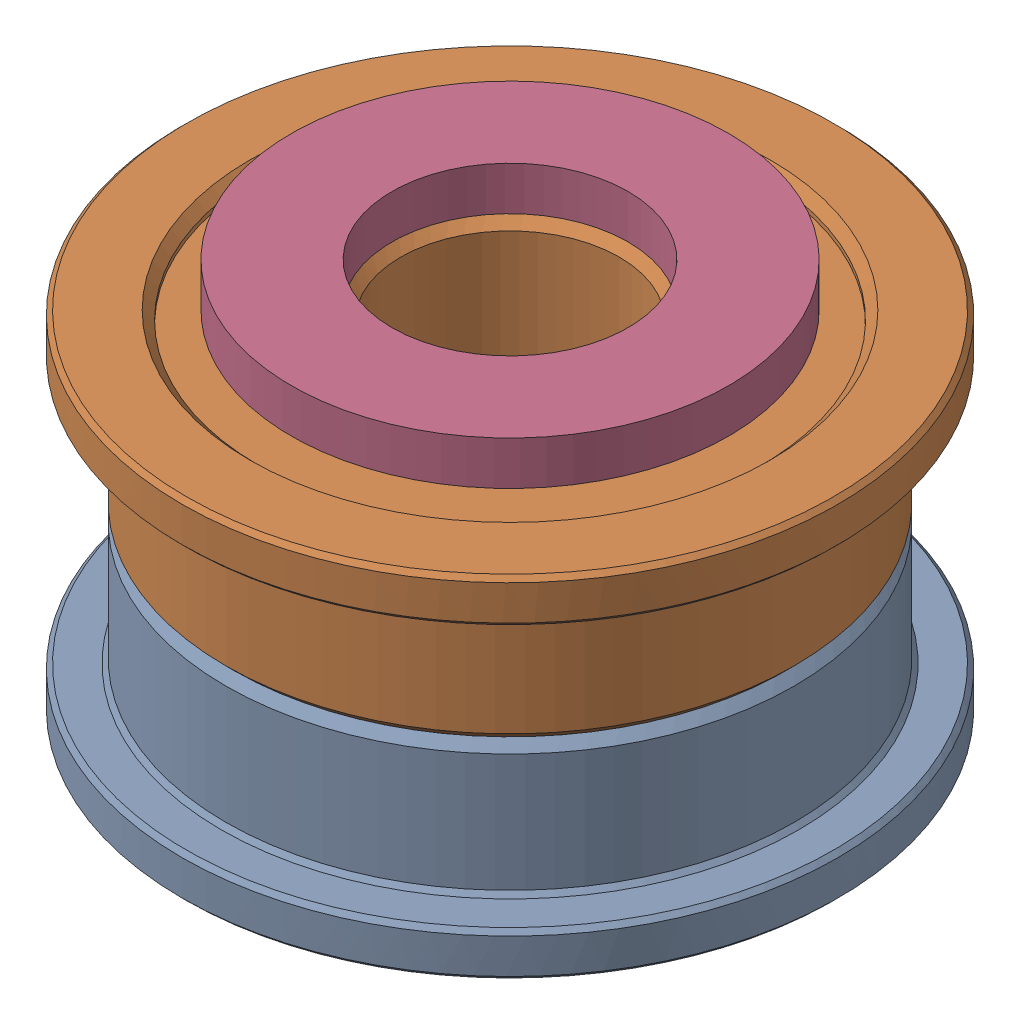
SolidWorks assembly Idler Pulley Assembly v3, configuration Default. Lengths in mm.
Overall size (15 10 15).
4 component instances, 3 part files, 0 mates.
Components (placement in the parent):
- F695-2RS v1 (1)-1: F695-2RS v1 (1) [Default] at origin size (15 4 15)
- F695-2RS v1 (2)-1: F695-2RS v1 (2) [Default] at (0 8 0) x (-1 0 0) z (0 0 1) size (15 4 15)
- M5 1mm Spacer-1: M5 1mm Spacer [Default] at (0 0 -350) size (10 1 10)
- M5 1mm Spacer-2: M5 1mm Spacer [Default] at (0 9 -350) size (10 1 10)
